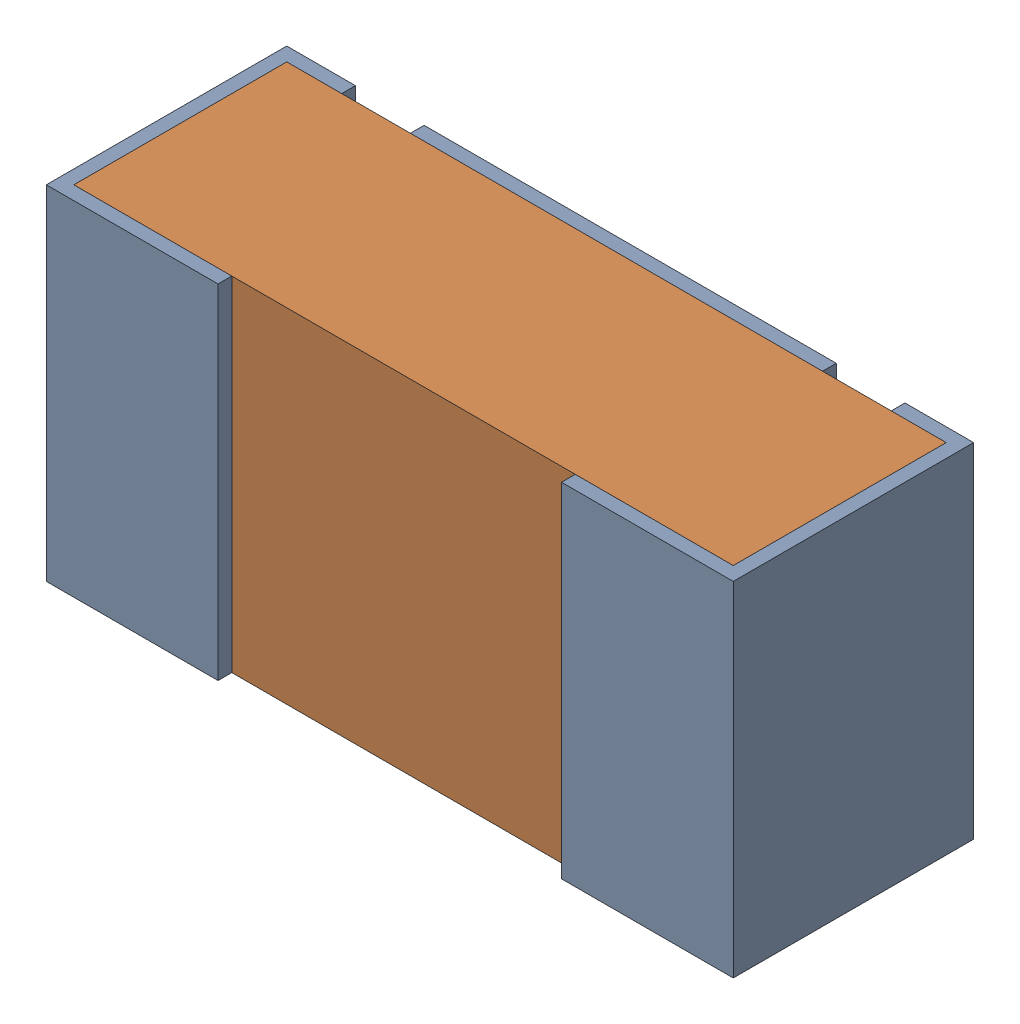
SolidWorks assembly R21, configuration Default. Lengths in mm.
Overall size (1 0.5 0.35).
3 component instances, 2 part files, 0 mates.
Components (placement in the parent):
- R21-subassembly-1-1: R21-subassembly-1 [Default] at (-1.4251 5.25 -1.6307) x (1 0 0) z (0 1 0) size (1 0.35 0.5)
  - 0402 resistor-1: 0402 resistor [Default] at origin size (1 0.35 0.5)
  - 0402 resistor-1-1: 0402 resistor-1 [Default] at origin size (0.96 0.31 0.5)
